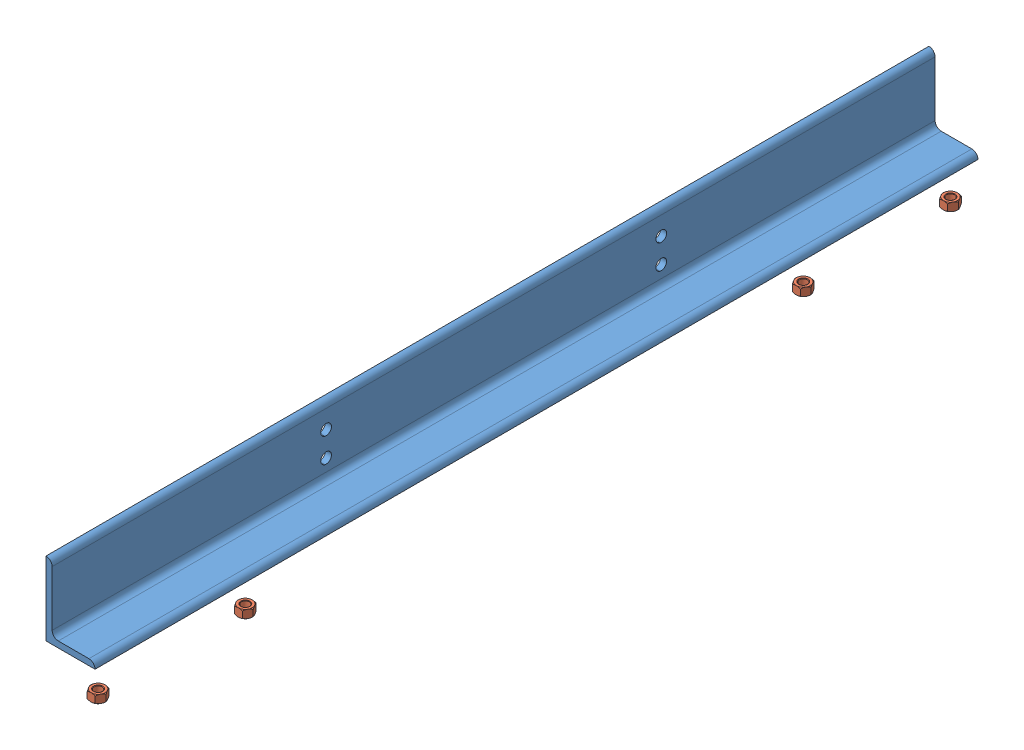
SolidWorks assembly 01-018-00-0, configuration Default. Lengths in mm.
Overall size (228.6 232.79 1828.8).
16 component instances, 4 part files, 5 mates.
Components (placement in the parent):
- 01-003-00-0-2: 01-003-00-0 [Default] at origin size (152.4 232.79 1828.8)
  - 01-004-00-0-3: 01-004-00-0 [Default] at (-6.35 0 0) size (101.6 152.4 1828.8)
  - Leg Support Ass-1: Leg Support Ass [Default] at (85.8425 -28.4478 -917.2083) x (0 0 -1) z (-1 0 0) size (63.5 80.39 152.4)
    - leg_2-1: leg_2 [TS2.5x2.5x0.1875x6] at (-66.3083 -28.4478 15.9925) size (63.5 63.5 152.4)
    - hex nut_ai-1: hex nut_ai [HNUT 0.7500-10-D-C] at (-34.5474 51.9432 15.9925) x (1 0 0) z (0 1 0) size (28.57 33 16.89)
  - Leg Support Ass-2: Leg Support Ass [Default] at (85.8425 -28.4478 -612.4083) x (0 0 -1) z (-1 0 0) size (63.5 80.39 152.4)
    - leg_2-1: leg_2 [TS2.5x2.5x0.1875x6] at (-66.3083 -28.4478 15.9925) size (63.5 63.5 152.4)
    - hex nut_ai-1: hex nut_ai [HNUT 0.7500-10-D-C] at (-34.5474 51.9432 15.9925) x (1 0 0) z (0 1 0) size (28.57 33 16.89)
  - Leg Support Ass-3: Leg Support Ass [Default] at (85.8425 -28.4478 543.2917) x (0 0 -1) z (-1 0 0) size (63.5 80.39 152.4)
    - leg_2-1: leg_2 [TS2.5x2.5x0.1875x6] at (-66.3083 -28.4478 15.9925) size (63.5 63.5 152.4)
    - hex nut_ai-1: hex nut_ai [HNUT 0.7500-10-D-C] at (-34.5474 51.9432 15.9925) x (1 0 0) z (0 1 0) size (28.57 33 16.89)
  - Leg Support Ass-4: Leg Support Ass [Default] at (85.8425 -28.4478 848.0917) x (0 0 -1) z (-1 0 0) size (63.5 80.39 152.4)
    - leg_2-1: leg_2 [TS2.5x2.5x0.1875x6] at (-66.3083 -28.4478 15.9925) size (63.5 63.5 152.4)
    - hex nut_ai-1: hex nut_ai [HNUT 0.7500-10-D-C] at (-34.5474 51.9432 15.9925) x (1 0 0) z (0 1 0) size (28.57 33 16.89)
- 01-017-00-0-2: 01-017-00-0 [Default] at (-82.55 0 31.75) x (1 0 0) z (0 -1 0) size (76.2 12.7 76.2)
- 01-017-00-0-3: 01-017-00-0 [Default] at (-82.55 76.2 -31.75) x (1 0 0) z (0 1 0) size (76.2 12.7 76.2)
Mates (geometry in assembly coordinates):
- Coincident4: coincident aligned: line of 01-003-00-0-2/01-004-00-0-3 through (-6.35 0 914.4) axis (0 0 -1); line of 01-017-00-0-2 through (-6.35 0 44.45) axis (0 0 -1)
- Coincident6: coincident anti-aligned: plane of 01-003-00-0-2/01-004-00-0-3 through (-6.35 0 914.4) normal (-1 0 0); plane of 01-017-00-0-3 through (-6.35 76.2 -44.45) normal (1 0 0)
- Coincident7: coincident anti-aligned: line of 01-003-00-0-2/01-004-00-0-3 through (-6.35 0 914.4) axis (0 0 -1); line of 01-017-00-0-3 through (-6.35 0 -44.45) axis (0 0 1)
- Distance1: distance = 869.95 mm aligned: plane of 01-003-00-0-2/01-004-00-0-3 through (-6.3449 139.7051 -914.4) normal (0 0 -1); plane of 01-017-00-0-3 through (-82.55 0 -44.45) normal (0 0 -1)
- Distance2: distance = 63.5 mm anti-aligned: plane of 01-017-00-0-3 through (-82.55 0 -31.75) normal (0 0 1); plane of 01-017-00-0-2 through (-82.55 76.2 31.75) normal (0 0 -1)
